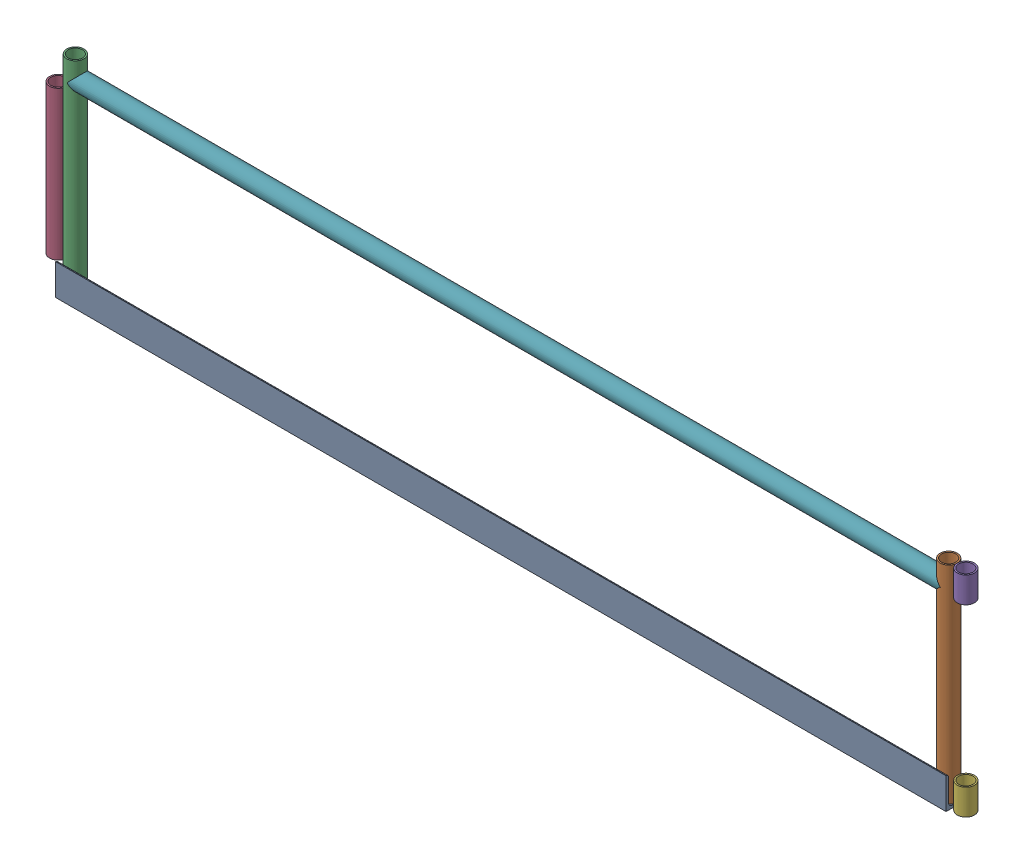
SolidWorks assembly GE-13015-L_ASM, configuration Default. Lengths in mm.
Overall size (2268.73 514.35 76.2).
7 component instances, 5 part files, 0 mates.
Components (placement in the parent):
- GE-13015-01-1: GE-13015-01 [Default] x (1 0 0) z (0 -1 0) size (2184.4 76.2 76.2)
- GE-13015-05-1: GE-13015-05 [Default] at (1071.118 260.35 -27.432) x (0 1 0) z (0 0 1) size (508 42.16 42.16)
- GE-13015-05-2: GE-13015-05 [Default] at (-1071.118 260.35 -27.432) x (0 1 0) z (0 0 1) size (508 42.16 42.16)
- GE-13015-04-1: GE-13015-04 [Default] at (-1113.282 252.4125 -27.432) x (0 1 0) z (0 0 1) size (365.12 42.16 42.16)
- GE-13015-03-1: GE-13015-03 [Default] at (1113.282 482.6 -27.432) x (0 -1 0) z (0 0 1) size (63.5 42.16 42.16)
- GE-13015-03-2: GE-13015-03 [Default] at (1113.282 31.75 -27.432) x (0 -1 0) z (0 0 1) size (63.5 42.16 42.16)
- GE-13015-02-1: GE-13015-02 [Default] at (-1071.118 463.55 -27.432) size (2143.25 42.16 42.16)
